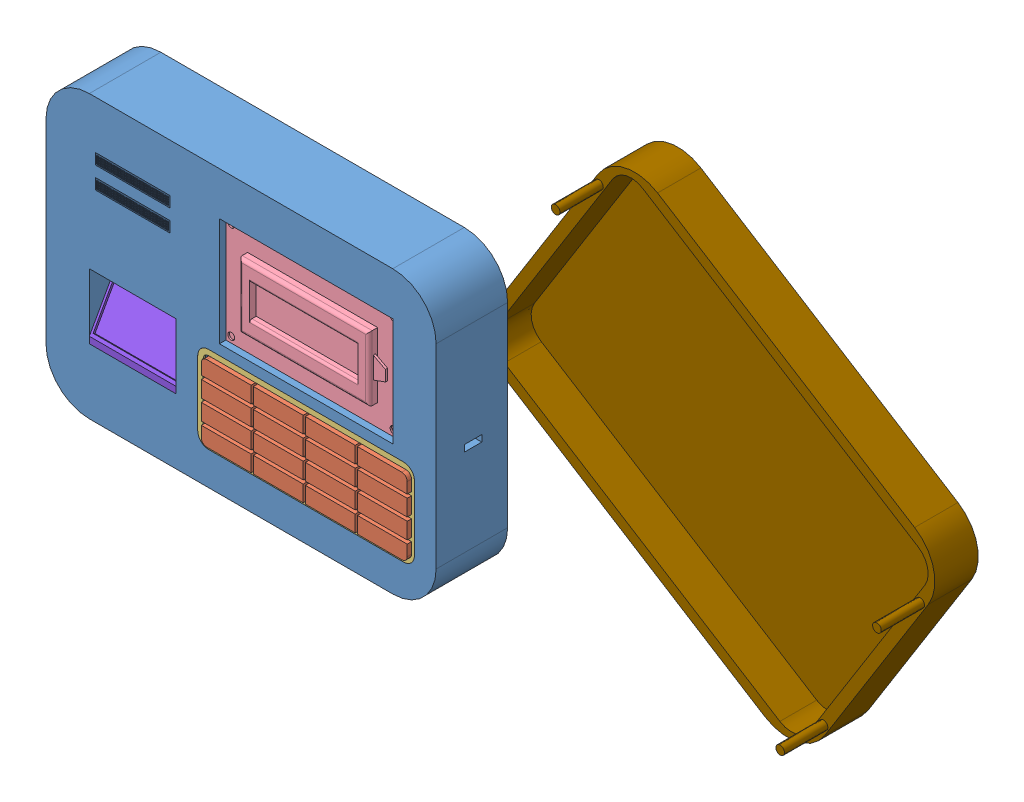
SolidWorks assembly Hasil, configuration Default. Lengths in mm.
Overall size (384.72 205.76 55).
15 component instances, 11 part files, 1 mates.
Components (placement in the parent):
- Z.ProggresAssembly_18-1: Z.ProggresAssembly_18 [Default] at (95.586 -157.9673 -197.5654) size (384.72 205.76 55)
  - CassingDepan_18-1: CassingDepan_18 [Default] at (52.3137 82.9745 159.9273) x (-1 0 0) z (0 0 -1) size (180 130 33)
  - KeypadBagianAkhir_18-1: KeypadBagianAkhir_18 [Default] at (59.288 133.2387 103.2217) x (1 0 0) z (0 -1 0) size (100 3 40)
    - KeypadBagian1_18-1: KeypadBagian1_18 [Default] at (40.5013 55.7056 69.4343) size (95 3 35)
    - KeypadBagian2_18-1: KeypadBagian2_18 [Default] at (53.1911 55.7056 77.0769) size (100 1 40)
  - lcd_18-1: lcd_18 [Default] at (71.0334 108.6696 154.9273) x (-1 0 0) z (0 1 0) size (80 6 50)
  - SpeakerBagianAkhir__18-2: SpeakerBagianAkhir__18 [Default] at (-0.7652 108.7976 122.6996) size (40 40 14.39)
    - SpeakerBagian1_18-1: SpeakerBagian1_18 [Default] at (7.6602 30.1689 28.2277) size (40 40 13)
    - SpeakerBagian2_18-1: SpeakerBagian2_18 [Default] at (16.4477 18.8141 27.8079) x (0 0 1) z (-1 0 0) size (3.6 38.15 38.15)
    - SpeakerBagian3_18-2: SpeakerBagian3_18 [Default] at (9.5625 18.9093 19.2277) x (1 0 0) z (0 -1 0) size (23 4 23)
  - sensor_18-3: sensor_18 [Default] at (-11.2026 72.1136 125.1815) x (0 0 -1) z (1 0 0) size (49 30 40)
  - CassingBelakang_18-1: CassingBelakang_18 [Default] at (245.0195 117.9422 106.9273) x (-0.847206 0.531265 0) z (0 0 1) size (180 130 40)
  - JaringSpeaker_18-1: JaringSpeaker_18 [Default] at (33.9961 99.3929 159.4273) size (34.54 5 0.5)
  - JaringSpeaker_18-2: JaringSpeaker_18 [Default] at (33.9961 89.3929 159.4273) size (34.54 5 0.5)
- Arduino_18-1: Arduino_18 [Default] at (229.3834 -5.2605 -49.6381) x (-1 0 0) z (0 -1 0) size (112.64 12 117)
Mates (geometry in assembly coordinates):
- Coincident1: coincident aligned: circle of Z.ProggresAssembly_18-1/CassingDepan_18-1; circle of Arduino_ kelompok 18-1
